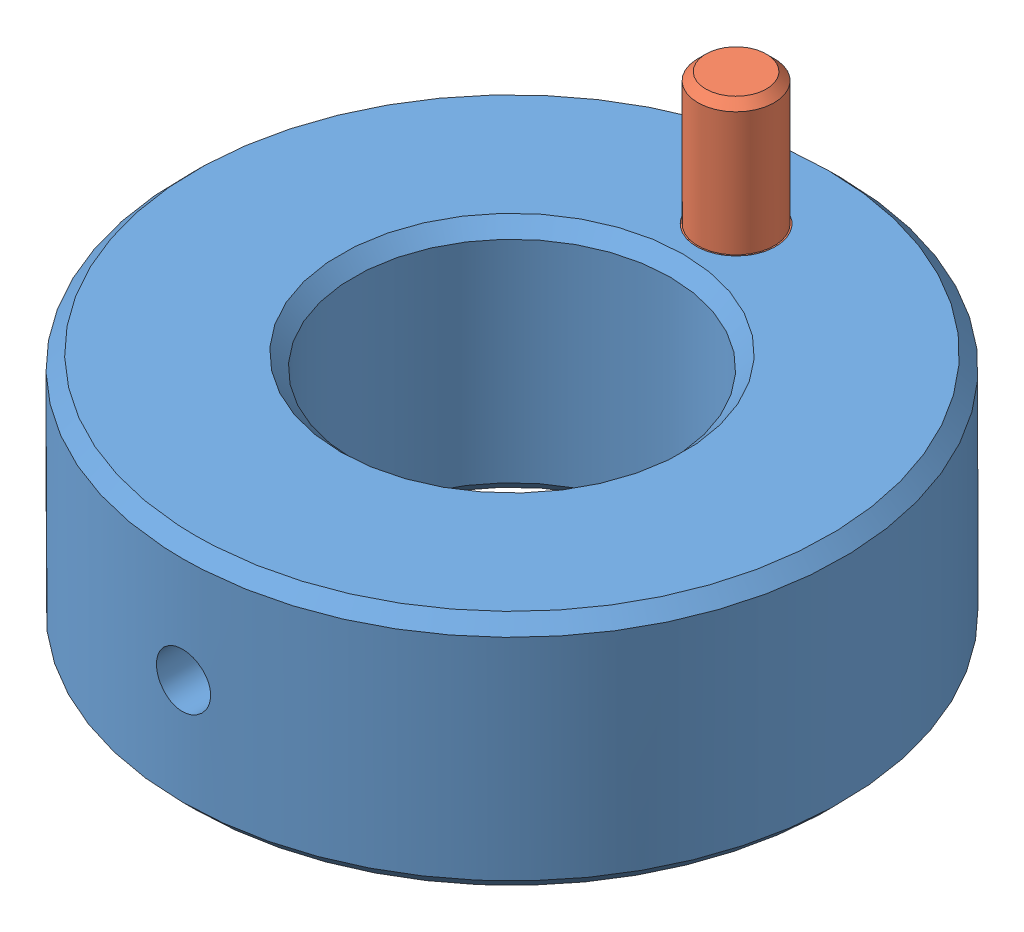
SolidWorks assembly ferrule ring, configuration Default. Lengths in mm.
Overall size (25 14 25).
2 component instances, 2 part files, 2 mates.
Components (placement in the parent):
- fibre ferrule ring-1: fibre ferrule ring [Default] at (12.3233 6.4069 19.0646) size (25 9 25)
- fibre ferrule ring pin-1: fibre ferrule ring pin [Default] at (12.3233 13.6144 10.5646) x (0 -1 0) z (-0.97433 0 -0.225124) size (10 3 3)
Mates (geometry in assembly coordinates):
- Concentric1: concentric aligned: cylinder of fibre ferrule ring-1 through (12.3233 15.4069 10.5646) axis (0 1 0) radius 1.55; cylinder of fibre ferrule ring pin-1 through (12.3233 16.1231 10.5646) axis (0 1 0) radius 1.5
- Coincident1: coincident aligned: circle of fibre ferrule ring-1; circle of fibre ferrule ring pin-1
